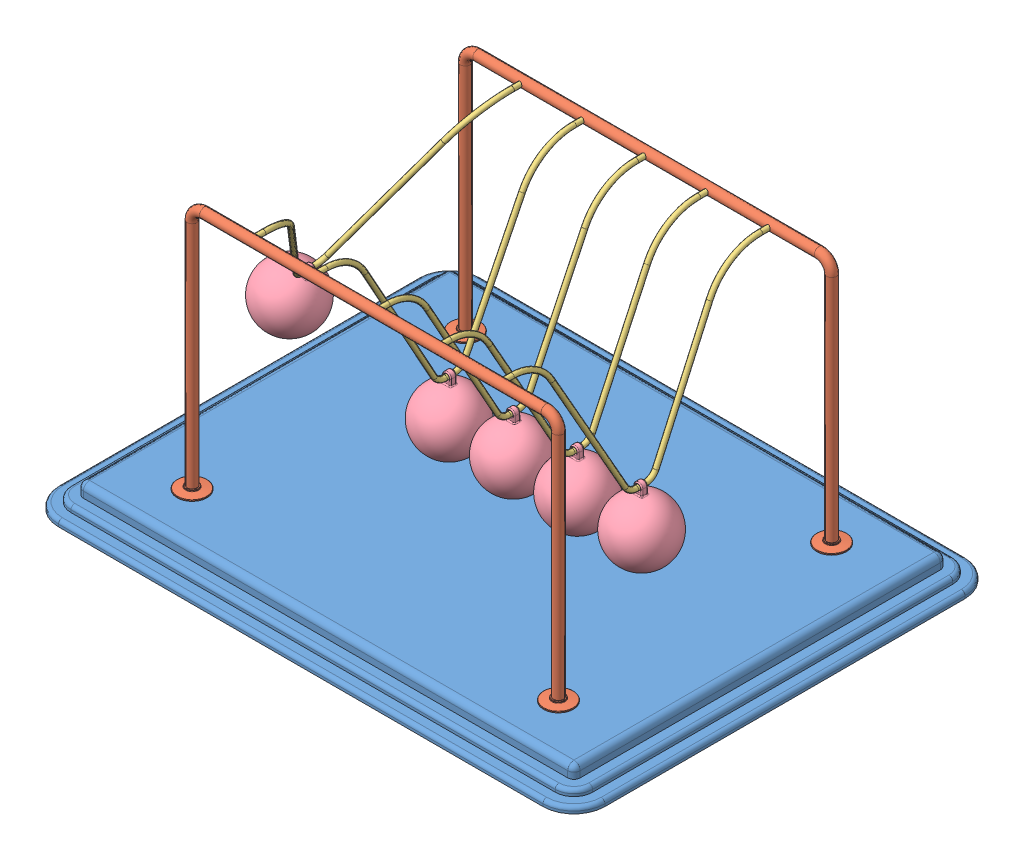
SolidWorks assembly Newtons Cradle 197,73095623987, configuration Default. Lengths in mm.
Overall size (440 222 340).
13 component instances, 4 part files, 34 mates.
Components (placement in the parent):
- Base NewtonsCradle 0244-1: Base NewtonsCradle 0244 [Default] at (-16.2968 -4.1587 11.425) size (440 20 340)
- frame NewtonsCradle 0244-1: frame NewtonsCradle 0244 [Default] at (-16.2968 144.4547 -98.575) size (319 202 24)
- frame NewtonsCradle 0244-2: frame NewtonsCradle 0244 [Default] at (-16.2968 144.4547 121.425) x (-1 0 0) z (0 0 -1) size (319 202 24)
- Hanging thing NewtonsCradle 0244-1: Hanging thing NewtonsCradle 0244 [Default] at (-157.6326 134.1825 11.425) x (0 0 1) z (-0.859985 0.510319 0) size (220 129 4)
- Hanging thing NewtonsCradle 0244-2: Hanging thing NewtonsCradle 0244 [Default] at (-66.576 122.8418 11.425) x (0 0 1) z (-0.999994 0.003446 0) size (220 129 4)
- Hanging thing NewtonsCradle 0244-3: Hanging thing NewtonsCradle 0244 [Default] at (-15.6923 122.8436 11.425) x (0 0 1) z (-0.999972 -0.007464 0) size (220 129 4)
- Hanging thing NewtonsCradle 0244-4: Hanging thing NewtonsCradle 0244 [Default] at (35.2213 122.8555 11.425) x (0 0 1) z (-0.999824 -0.018742 0) size (220 129 4)
- Hanging thing NewtonsCradle 0244-5: Hanging thing NewtonsCradle 0244 [Default] at (86.0287 122.8747 11.425) x (0 0 1) z (-0.999588 -0.028711 0) size (220 129 4)
- Sphere NewtonsCradle 0244-1: Sphere NewtonsCradle 0244 [Default] at (-195.3962 70.5436 11.425) x (0.859985 -0.510319 0) z (0 0 1) size (50 58.5 50)
- Sphere NewtonsCradle 0244-2: Sphere NewtonsCradle 0244 [Default] at (88.1533 48.9052 11.425) x (0.999588 0.028711 0) z (0 0 1) size (50 58.5 50)
- Sphere NewtonsCradle 0244-3: Sphere NewtonsCradle 0244 [Default] at (-15.14 48.8456 11.425) x (0.999972 0.007464 0) z (0 0 1) size (50 58.5 50)
- Sphere NewtonsCradle 0244-4: Sphere NewtonsCradle 0244 [Default] at (36.6081 48.8685 11.425) x (0.999824 0.018742 0) z (0 0 1) size (50 58.5 50)
- Sphere NewtonsCradle 0244-5: Sphere NewtonsCradle 0244 [Default] at (-66.831 48.8422 11.425) x (0.999994 -0.003446 0) z (0 0 1) size (50 58.5 50)
Mates (geometry in assembly coordinates):
- Coincident1: coincident anti-aligned: plane of Base-1 through (-211.2968 5.8413 156.425) normal (0 1 0); plane of frame-2 through (-175.7968 5.8413 121.425) normal (0 -1 0)
- Coincident2: coincident anti-aligned: plane of Base-1 through (-211.2968 5.8413 156.425) normal (0 1 0); plane of frame-1 through (143.2032 5.8413 -98.575) normal (0 -1 0)
- Concentric1: concentric anti-aligned: cylinder of frame-1 through (-116.2968 203.8413 -94.575) axis (0 0 -1) radius 2; cylinder of frame-2 through (-116.2968 203.8413 117.425) axis (0 0 1) radius 2
- Concentric2: concentric anti-aligned: cylinder of frame-1 through (83.7032 203.8413 -94.575) axis (0 0 -1) radius 2; cylinder of frame-2 through (83.7032 203.8413 117.425) axis (0 0 1) radius 2
- Distance1: distance = 60 mm: plane of frame-1 through (-16.2968 144.4547 -98.575) normal (0 0 1); line of Base-1 through (-211.2968 -12.1587 -158.575) axis (1 0 0)
- Distance2: distance = 60 mm: line of Base-1 through (178.7032 -12.1587 181.425) axis (-1 0 0); plane of frame-2 through (-16.2968 144.4547 121.425) normal (0 0 -1)
- Distance3: distance = 220 mm: plane of frame-2 through (-16.2968 144.4547 121.425) normal (-1 0 0); line of Base-1 through (-236.2968 -12.1587 156.425) axis (0 0 -1)
- Concentric3: concentric anti-aligned: cylinder of frame-1 through (-116.2968 203.8413 -94.575) axis (0 0 -1) radius 2; cylinder of Hanging thing-1 through (-116.2968 203.8413 111.425) axis (0 0 1) radius 2
- Concentric4: concentric anti-aligned: cylinder of frame-1 through (-116.2968 203.8413 -94.575) axis (0 0 -1) radius 2; cylinder of Hanging thing-1 through (-116.2968 203.8413 -98.575) axis (0 0 1) radius 2
- Concentric5: concentric aligned: cylinder of frame-2 through (-66.2968 203.8413 117.425) axis (0 0 1) radius 2; cylinder of Hanging thing-2 through (-66.2968 203.8413 111.425) axis (0 0 1) radius 2
- Concentric6: concentric aligned: cylinder of frame-2 through (-16.2968 203.8413 117.425) axis (0 0 1) radius 2; cylinder of Hanging thing-3 through (-16.2968 203.8413 111.425) axis (0 0 1) radius 2
- Concentric7: concentric aligned: cylinder of frame-2 through (33.7032 203.8413 117.425) axis (0 0 1) radius 2; cylinder of Hanging thing-4 through (33.7032 203.8413 111.425) axis (0 0 1) radius 2
- Concentric8: concentric aligned: cylinder of frame-2 through (83.7032 203.8413 117.425) axis (0 0 1) radius 2; cylinder of Hanging thing-5 through (83.7032 203.8413 111.425) axis (0 0 1) radius 2
- Coincident5: coincident anti-aligned: plane of frame-2 through (83.7032 203.8413 121.425) normal (0 0 -1); plane of Hanging thing-5 through (83.7032 203.8413 121.425) normal (0 0 1)
- Coincident6: coincident anti-aligned: plane of frame-2 through (33.7032 203.8413 121.425) normal (0 0 -1); plane of Hanging thing-4 through (33.7032 203.8413 121.425) normal (0 0 1)
- Coincident7: coincident anti-aligned: plane of frame-2 through (-16.2968 203.8413 121.425) normal (0 0 -1); plane of Hanging thing-3 through (-16.2968 203.8413 121.425) normal (0 0 1)
- Coincident8: coincident anti-aligned: plane of frame-2 through (-66.2968 203.8413 121.425) normal (0 0 -1); plane of Hanging thing-2 through (-66.2968 203.8413 121.425) normal (0 0 1)
- Coincident9: coincident anti-aligned: plane of frame-2 through (-116.2968 203.8413 121.425) normal (0 0 -1); plane of Hanging thing-1 through (-116.2968 203.8413 121.425) normal (0 0 1)
- Concentric9: concentric anti-aligned: cylinder of Hanging thing-1 through (-117.0163 78.8434 7.925) axis (0 0 1) radius 2; cylinder of Sphere-1 through (-117.0163 78.8434 13.925) axis (0 0 -1) radius 2
- Concentric13: concentric anti-aligned: cylinder of Hanging thing-2 through (-66.7276 78.842 7.925) axis (0 0 1) radius 2; cylinder of Sphere-5 through (-66.7276 78.842 13.925) axis (0 0 -1) radius 2
- Concentric15: concentric anti-aligned: cylinder of Hanging thing-3 through (-15.3639 78.8448 7.925) axis (0 0 1) radius 2; cylinder of Sphere-3 through (-15.3639 78.8448 13.925) axis (0 0 -1) radius 2
- Concentric16: concentric anti-aligned: cylinder of Hanging thing-5 through (87.292 78.8928 7.925) axis (0 0 1) radius 2; cylinder of Sphere-2 through (87.292 78.8928 13.925) axis (0 0 -1) radius 2
- Concentric17: concentric anti-aligned: cylinder of Hanging thing-4 through (36.0459 78.8632 7.925) axis (0 0 1) radius 2; cylinder of Sphere-4 through (36.0459 78.8632 13.925) axis (0 0 -1) radius 2
- Parallel1: parallel anti-aligned: plane of Hanging thing-1; plane of Sphere-1
- Coincident22: coincident anti-aligned: plane of Hanging thing-1; plane of Sphere-1
- Coincident12: coincident aligned: plane of Hanging thing-2 through (-66.576 122.8418 11.425) normal (0 0 1); plane of Sphere-5 through (-66.831 48.8422 11.425) normal (0 0 1)
- Coincident10: coincident aligned: plane of Hanging thing-1 through (-116.763 122.8426 11.425) normal (0 0 1); plane of Sphere-1 through (-118.5806 48.8842 11.425) normal (0 0 1)
- Coincident13: coincident anti-aligned: plane of Hanging thing-2 through (-66.576 122.8418 11.425) normal (-0.999994 0.003446 0); plane of Sphere-5 through (-66.831 48.8422 11.425) normal (0.999994 -0.003446 0)
- Coincident14: coincident anti-aligned: plane of Hanging thing-3 through (-15.6923 122.8436 11.425) normal (-0.999972 -0.007464 0); plane of Sphere-3 through (-15.14 48.8456 11.425) normal (0.999972 0.007464 0)
- Coincident15: coincident aligned: plane of Hanging thing-3 through (-15.6923 122.8436 11.425) normal (0 0 1); plane of Sphere-3 through (-15.14 48.8456 11.425) normal (0 0 1)
- Coincident18: coincident aligned: plane of Hanging thing-4 through (35.2213 122.8555 11.425) normal (0 0 1); plane of Sphere-4 through (36.6081 48.8685 11.425) normal (0 0 1)
- Coincident19: coincident anti-aligned: plane of Hanging thing-4 through (35.2213 122.8555 11.425) normal (-0.999824 -0.018742 0); plane of Sphere-4 through (36.6081 48.8685 11.425) normal (0.999824 0.018742 0)
- Coincident20: coincident anti-aligned: plane of Hanging thing-5 through (86.0287 122.8747 11.425) normal (-0.999588 -0.028711 0); plane of Sphere-2 through (88.1533 48.9052 11.425) normal (0.999588 0.028711 0)
- Coincident21: coincident aligned: plane of Hanging thing-5 through (86.0287 122.8747 11.425) normal (0 0 1); plane of Sphere-2 through (88.1533 48.9052 11.425) normal (0 0 1)
